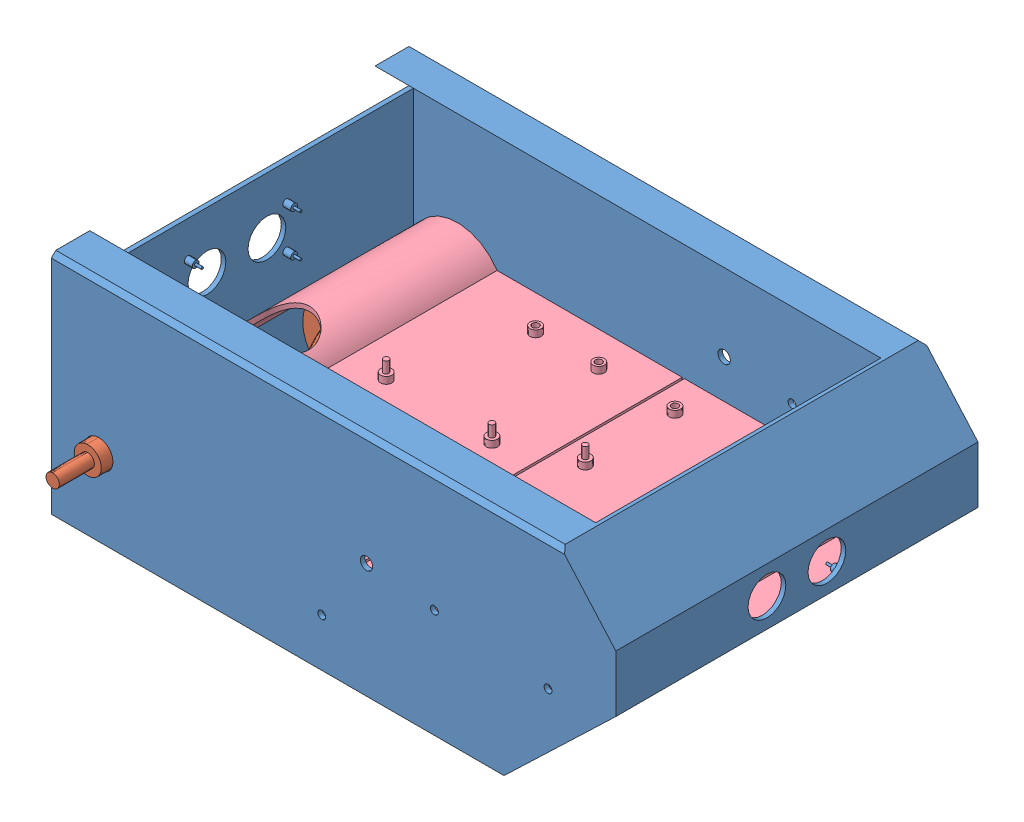
SolidWorks assembly 1_Layer, configuration Standard. Lengths in mm.
Overall size (249.41 100 200.8).
5 component instances, 4 part files, 10 mates.
Components (placement in the parent):
- Box-1: Box [Standard] at (-47.2891 -14.6729 181.4058) size (249.41 100 160)
- motor.step-1: motor.step [Standard] at (-129.417 -32.1678 288.0058) x (-0.998685 -0.051266 0) z (-0.051266 0.998685 0) size (37.1 151.83 37.1)
- motor.step-2: motor.step [Standard] at (-129.1821 -32.1532 234.8058) x (0.997374 0.072429 0) z (-0.072429 0.997374 0) size (37.1 151.83 37.1)
- Battery-1: Battery [Standard] at (-4.7032 -18.9273 234.9058) size (142 30 52)
- Layer-2_Mounting-2: Layer-2_Mounting [Standard] at (50.7363 -22.6924 339.1558) x (-1 0 0) z (0 0 -1) size (216.69 23.92 155.5)
Mates (geometry in assembly coordinates):
- Concentric1: concentric: circle of Box-1; cylinder of motor.step-1 through (-129.986 -21.0824 361.8058) axis (0 0 -1) radius 2.95
- Concentric2: concentric anti-aligned: circle of Box-1; circle of motor.step-2
- Coincident4: coincident aligned: line of Box-1 through (-97.486 -52.6924 287.9058) axis (0 0 -1); line of Battery-1 through (-97.486 -52.6924 286.9058) axis (0 0 -1)
- Coincident5: coincident aligned: line of Box-1 through (-97.486 -52.6924 234.9058) axis (1 0 0); line of Battery-1 through (-97.486 -52.6924 234.9058) axis (1 0 0)
- Coincident6: coincident: plane of Box-1 through (-47.2891 -14.6729 339.4058) normal (0 0 -1); circle of motor.step-1
- Coincident7: coincident anti-aligned: plane of Box-1 through (-47.2891 -14.6729 183.4058) normal (0 0 1); circle of motor.step-2
- Parallel1: parallel: plane of Box-1 through (-150.986 -52.6924 341.4058) normal (0 1 0); line of motor.step-1 through (-130.3052 -14.8656 317.4058) axis (0 0 -1)
- Coincident15: coincident anti-aligned: plane of Battery-1 through (-97.486 -22.6924 286.9058) normal (0 1 0); plane of Layer-2_Mounting-2 through (-107.4768 -22.6924 183.6558) normal (0 -1 0)
- Concentric5: concentric anti-aligned: cylinder of motor.step-1 through (-129.417 -32.1678 339.4058) axis (0 0 -1) radius 18.55; cylinder of Layer-2_Mounting-2 through (-129.417 -32.1678 183.6558) axis (0 0 1) radius 19.05
- Distance1: distance = 0.25 mm anti-aligned: plane of Layer-2_Mounting-2 through (-129.417 -32.1678 183.6558) normal (0 0 -1); plane of Box-1 through (-47.2891 -14.6729 183.4058) normal (0 0 1)
